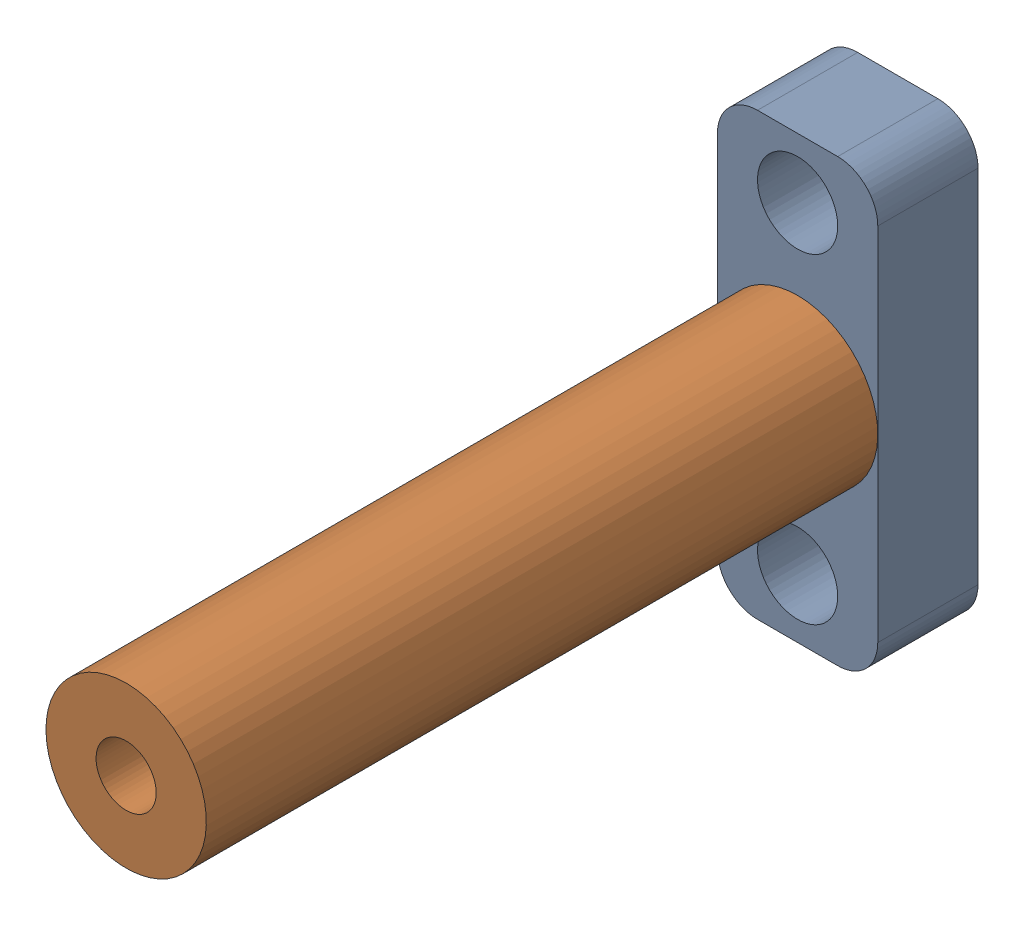
SolidWorks assembly Assem2, configuration Default. Lengths in mm.
Overall size (10.45 22 38.5).
2 component instances, 2 part files, 2 mates.
Components (placement in the parent):
- Bus3-1-1: Bus3-1 [Default] at origin size (8 22 5)
- Bus1_part-1: Bus1_part [Default] at (4 0 38.5) x (-0.923728 -0.383049 0) z (0 0 -1) size (8 8 38.5)
Mates (geometry in assembly coordinates):
- Coincident1: coincident anti-aligned: plane of Bus3-1-1 through (6 9 5) normal (0 0 1); plane of Bus1_part-1 through (4 0 5) normal (0 0 -1)
- Concentric1: concentric anti-aligned: circle of Bus3-1-1; circle of Bus1_part-1
